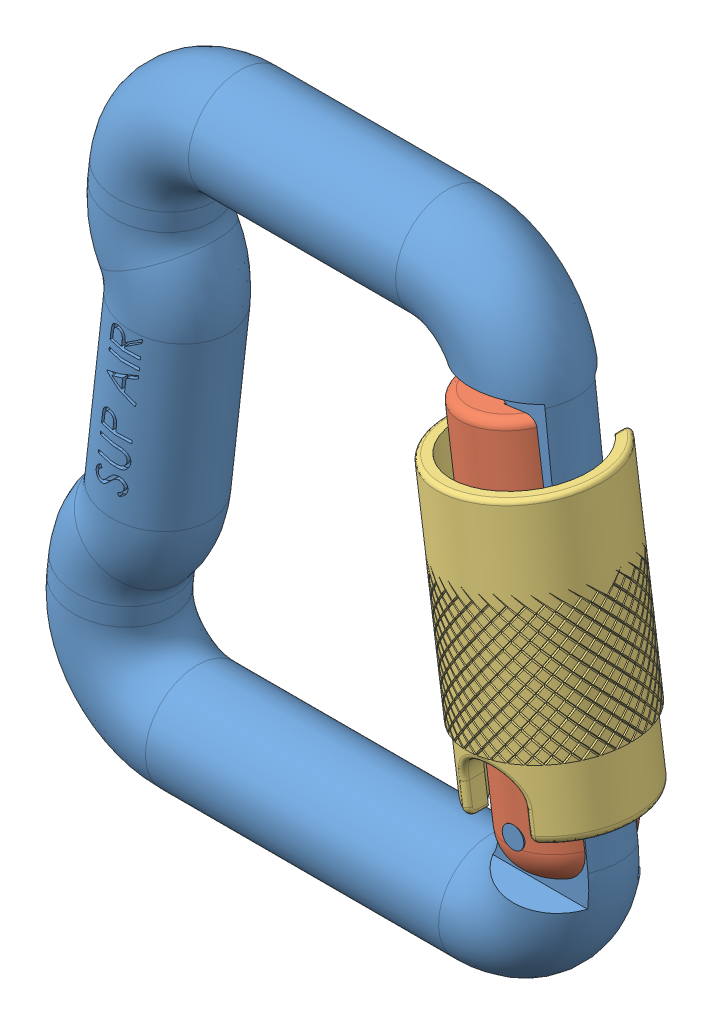
SolidWorks assembly CARABINER SUP AIR Ø12, configuration Default. Lengths in mm.
Overall size (66.23 74 18.01).
3 component instances, 3 part files, 4 mates.
Components (placement in the parent):
- ALÇA-1: ALÇA [Default] at origin size (63.85 74 12.79)
- GATILHO-1: GATILHO [Default] at (26.2233 -22.952 0) x (0.990404 0.138202 0) z (0 0 1) size (12 45.37 12.12)
- FECHO-1: FECHO [Default] at (25.3718 -16.8504 0) x (0.990404 0.138202 0) z (0 0 1) size (18.01 33.07 18.01)
Mates (geometry in assembly coordinates):
- Coincident1: coincident aligned: plane of GATILHO-1 through (25.9507 -22.4648 0) normal (0 0 1); plane of assembly through (0 0 0) normal (0 0 1)
- Concentric2: concentric aligned: cylinder of GATILHO-1 through (19.7316 22.1034 0) axis (0.138202 -0.990404 0) radius 6; cylinder of FECHO-1 through (20.6105 15.8049 0) axis (0.138202 -0.990404 0) radius 9
- Coincident2: coincident aligned: plane of FECHO-1 through (25.1712 -16.8784 0) normal (0 0 1); plane of assembly through (0 0 0) normal (0 0 1)
- Concentric4: concentric anti-aligned: cylinder of ALÇA-1 through (25.5323 -18 6) axis (0 0 -1) radius 1.25; cylinder of GATILHO-1 through (25.5323 -18 -6) axis (0 0 1) radius 1.25
